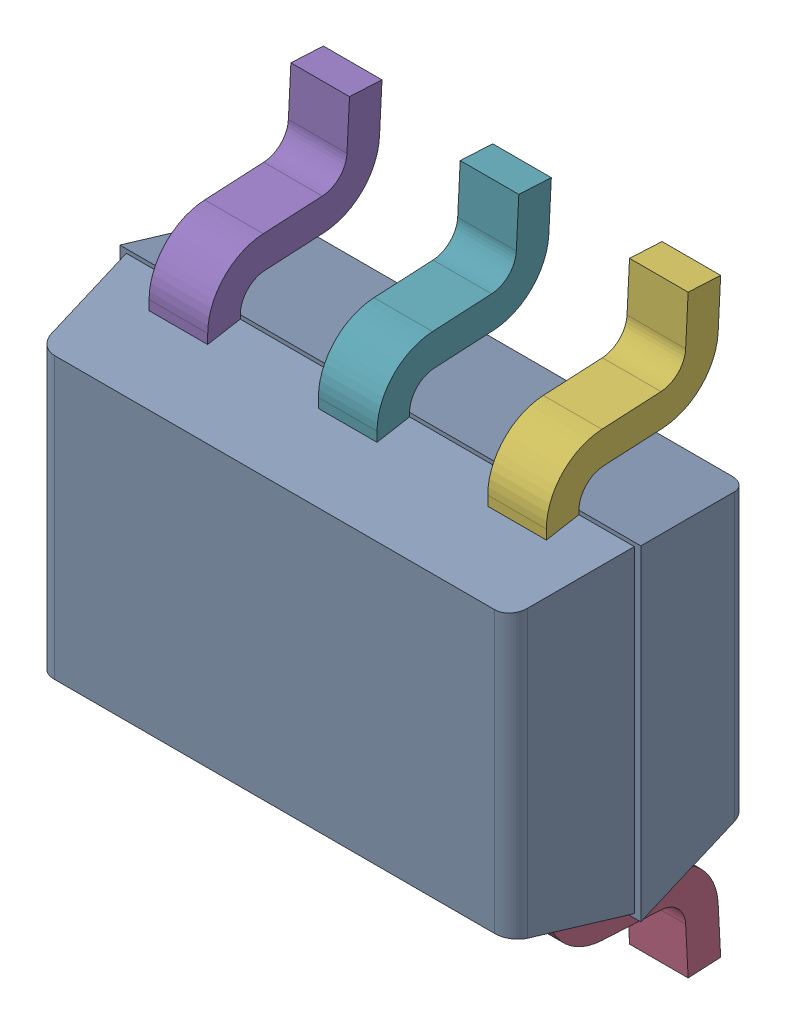
SolidWorks assembly D1, configuration Default. Lengths in mm.
Overall size (2 2.28 0.95).
9 component instances, 7 part files, 0 mates.
Components (placement in the parent):
- DCK0006A-1: DCK0006A [Default] at (3.81 35.0519 0.544) x (-1 0 0) z (0 -1 0) size (2 0.95 2.28)
  - DCK0006A_2-1: DCK0006A_2 [Default] at origin size (2 0.9 1.25)
  - DCK0006A_1-1: DCK0006A_1 [Default] at (0.65 0 0) x (0 0 1) z (1 0 0) size (2.28 0.67 1.53)
    - DCK0006A_3-1: DCK0006A_3 [Default] at origin size (0.55 0.67 0.23)
    - DCK0006A_4-1: DCK0006A_4 [Default] at origin size (0.55 0.67 0.23)
    - DCK0006A_5-1: DCK0006A_5 [Default] at origin size (0.55 0.67 0.23)
    - DCK0006A_6-1: DCK0006A_6 [Default] at origin size (0.55 0.67 0.23)
    - DCK0006A_7-1: DCK0006A_7 [Default] at origin size (0.55 0.67 0.23)
    - DCK0006A_8-1: DCK0006A_8 [Default] at origin size (0.55 0.67 0.23)
